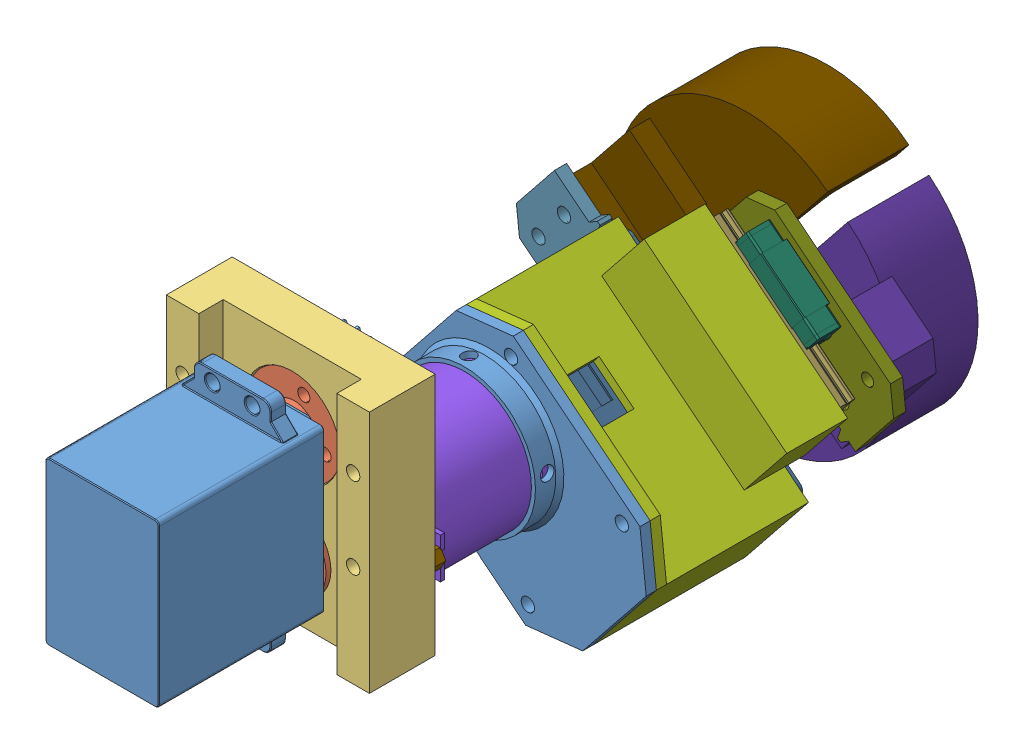
SolidWorks assembly Turntable assembly, configuration close. Lengths in mm.
Overall size (99.15 95.23 181.35).
25 component instances, 20 part files, 72 mates.
Components (placement in the parent):
- SM29BL-1: SM29BL [預設] at (0 0 1.5) size (28 54 48.8)
- SMS Servo Disc-1: SMS Servo Disc [預設] at (0 10 -8) x (-0.299611 -0.954061 0) z (0 0 1) size (23 23 6)
- Gear mount-1: Gear mount [預設] at (0 28.5 1.45) x (-1 0 0) z (0 -1 0) size (50 16.2 60)
- Gear spacer-1: Gear spacer [預設] at (0 10 -16) x (-0.299611 -0.954061 0) z (0 0 1) size (23 23 8)
- 1M 26T 4mm SMS hub-1: 1M 26T 4mm SMS hub [預設] at (0 10 -20) x (-0.299611 -0.954061 0) z (0 0 1) size (28 27.86 4)
- 1M 26T 4mm SMS hub-2: 1M 26T 4mm SMS hub [預設] at (0 -16 -19.95) x (-0.223358 0.974736 0) z (0 0 1) size (28 27.86 4)
- Washer_8x15x1.6mm-1: Washer_8x15x1.6mm [預設] at (0 -16 -21.55) size (15.32 15.32 1.62)
- Turntable Servo Mount-1: Turntable Servo Mount [預設] at (7.5485 -22.052 -92.95) x (0.625526 0.780203 0) z (0 0 1) size (58.5 60 42.5)
- Slip Ring-1: Slip Ring [預設] at (0 -16 -46.95) size (41 33 32.4)
- M3x6+5-1: M3x6+5 [預設] at (19 -16 -20.75) size (5.26 4.56 11)
- M3x6+5-2: M3x6+5 [預設] at (-19 -16 -20.75) size (5.26 4.56 11)
- UART Servo-1: UART Servo [預設] at (7.5485 -22.052 -86.25) x (0.780203 -0.625526 0) z (0 0 -1) size (56 22.53 44.45)
- Servo disc-1: Servo disc [Default] at (0 -16 -107.1) x (-0.33197 -0.94329 0) z (-0.94329 0.33197 0) size (20 4.5 20)
- MGN7 rail-1: MGN7 rail [70 mm] at (7.9835 -53.4824 -100.35) x (0.625526 0.780203 0) z (-0.780203 0.625526 0) size (7 4.8 40)
- MGN7 rail-2: MGN7 rail [70 mm] at (38.3215 -15.6426 -100.35) x (0.625526 0.780203 0) z (-0.780203 0.625526 0) size (7 4.8 40)
- 1M 26T 4mm SCS hub-1: 1M 26T 4mm SCS hub [預設] at (0 -16 -111.1) x (0.901745 0.432268 0) z (0 0 1) size (28 27.86 4)
- Turntable rack left-1: Turntable rack left [預設] at (-19.1907 -31.6956 -106.05) x (-0.780203 0.625526 0) z (0 0 -1) size (61.5 22.25 3)
- MGN7C-1: MGN7C [MGN7C] at (20.439 -1.3053 -102.8) x (0.625526 0.780203 0) z (-0.780203 0.625526 0) size (17 6.5 23.31)
- MGN7C-2: MGN7C [MGN7C] at (-5.3421 -42.7987 -102.8) x (0.625526 0.780203 0) z (-0.780203 0.625526 0) size (17 6.5 23.31)
- Turntable rack right-1: Turntable rack right [預設] at (25.3153 -5.2148 -106.05) x (0.780203 -0.625526 0) z (0 0 -1) size (46.5 22.25 3)
- Turntable Gripper Right-1: Turntable Gripper Right [預設] at (51.253 43.5228 -139.05) x (-0.780203 0.625526 0) z (0 0 1) size (35.43 66.5 30)
- Turntable Gripper left-1: Turntable Gripper left [預設] at (-2.8123 -13.7452 -139.05) x (-0.780203 0.625526 0) z (0 0 1) size (35.43 66.5 30)
- Turntable axle-1: Turntable axle [預設] at (7.5485 -22.052 -92.95) x (0.625526 0.780203 0) z (0 0 1) size (45 60 51.6)
- F697ZZ_7x17x5mm-1: F697ZZ_7x17x5mm [預設] at (0 -16 -9.75) x (-0.997972 -0.063648 0) z (0 0 -1) size (19 19 6.2)
- F697ZZ_7x17x5mm-2: F697ZZ_7x17x5mm [預設] at (0 -16 -9.55) x (-0.081847 0.996645 0) z (0 0 1) size (19 19 6.2)
Mates (geometry in assembly coordinates):
- 同軸心1: concentric anti-aligned: cylinder of SM29BL-1 through (0 10 -1.5) axis (0 0 -1) radius 1.1; cylinder of SMS Servo Disc-1 through (0 10 -8.001) axis (0 0 1) radius 1.65
- 重合/共線/共點1: coincident anti-aligned: plane of SM29BL-1 through (0 0 -6.5) normal (0 0 -1); plane of SMS Servo Disc-1 through (0 10 -6.5) normal (0 0 1)
- 重合/共線/共點2: coincident anti-aligned: plane of SM29BL-1 through (0 0 0) normal (0 0 -1)
- 同軸心2: concentric aligned: cylinder of SMS Servo Disc-1 through (0 10 -5) axis (0 0 -1) radius 11.5; cylinder of Gear mount-1 through (0 10 25.25) axis (0 0 -1) radius 11.75
- 平行1: parallel aligned: plane of SM29BL-1 through (14 20 42.3) normal (1 0 0); plane of Gear mount-1 through (25 -31.5 -14.75) normal (1 0 0)
- 同軸心3: concentric aligned: cylinder of Gear mount-1 through (0 -16 25.25) axis (0 0 -1) radius 9.5; cylinder of F607ZZ_7x19x6mm-1 through (0 -16 -5.55) axis (0 0 -1) radius 9.5
- 重合/共線/共點3: coincident anti-aligned: plane of Gear mount-1 through (-25 -31.5 -14.75) normal (0 0 -1); plane of F607ZZ_7x19x6mm-1 through (0 -16 -11.55) normal (0 0 1)
- 同軸心4: concentric aligned: cylinder of SMS Servo Disc-1 through (7.6325 7.6031 -5) axis (0 0 -1) radius 1.5; cylinder of Gear spacer-1 through (7.6325 7.6031 -8) axis (0 0 -1) radius 1.65
- 同軸心5: concentric anti-aligned: cylinder of SMS Servo Disc-1 through (0 10 -8.001) axis (0 0 1) radius 1.65; cylinder of Gear spacer-1 through (0 10 -8) axis (0 0 -1) radius 2.1
- 同軸心6: concentric anti-aligned: cylinder of Gear spacer-1 through (-2.3969 2.3675 -8) axis (0 0 -1) radius 1.65; cylinder of 1M 26T 4mm SMS hub-1 through (-2.3969 2.3675 -20.001) axis (0 0 1) radius 1.65
- 同軸心8: concentric anti-aligned: cylinder of Gear spacer-1 through (0 10 -8) axis (0 0 -1) radius 2.1; cylinder of 1M 26T 4mm SMS hub-1 through (0 10 -20.001) axis (0 0 1) radius 3.6
- 同軸心9: concentric anti-aligned: cylinder of F607ZZ_7x19x6mm-1 through (0 -16 -5.55) axis (0 0 -1) radius 3.5; cylinder of 1M 26T 4mm SMS hub-2 through (0 -16 -19.951) axis (0 0 1) radius 3.6
- 齒輪結合1: gear = 26 : 26 mm: circle of 1M 26T 4mm SMS hub-2; circle of 1M 26T 4mm SMS hub-1
- 相互對稱1: symmetric aligned: plane of SM29BL-1 through (-14 20 42.3) normal (0 1 0); plane of SM29BL-1 through (-14 -20 42.3) normal (0 -1 0)
- 相互對稱2: symmetric aligned: plane of SM29BL-1 through (14 20 42.3) normal (1 0 0); plane of SM29BL-1 through (-14 20 42.3) normal (-1 0 0)
- 重合/共線/共點7: coincident anti-aligned: plane of SMS Servo Disc-1 through (0 10 -8) normal (0 0 -1); plane of Gear spacer-1 through (0 10 -8) normal (0 0 1)
- 重合/共線/共點8: coincident anti-aligned: plane of Gear spacer-1 through (0 10 -16) normal (0 0 -1); plane of 1M 26T 4mm SMS hub-1 through (0 10 -16) normal (0 0 1)
- 重合/共線/共點9: coincident anti-aligned: plane of 1M 26T 4mm SMS hub-2 through (0 -16 -19.95) normal (0 0 -1); plane of Washer_8x15x1.6mm-1 through (0 -16 -19.95) normal (0 0 1)
- 同軸心10: concentric anti-aligned: cylinder of 1M 26T 4mm SMS hub-2 through (0 -16 -19.951) axis (0 0 1) radius 3.6; cylinder of Washer_8x15x1.6mm-1 through (0 -16 -19.95) axis (0 0 -1) radius 4
- 重合/共線/共點10: coincident anti-aligned: plane of Washer_8x15x1.6mm-1 through (0 -16 -21.55) normal (0 0 -1); plane of Slip Ring-1 through (8.5 -21 -21.55) normal (0 0 1)
- 同軸心11: concentric anti-aligned: cylinder of Washer_8x15x1.6mm-1 through (0 -16 -19.95) axis (0 0 -1) radius 4; cylinder of Slip Ring-1 through (0 -16 -46.951) axis (0 0 1) radius 3.5
- 平行2: parallel aligned: plane of Gear mount-1 through (25 -31.5 -14.75) normal (1 0 0); plane of Slip Ring-1 through (20.5 -21 -20.55) normal (1 0 0)
- 同軸心14: concentric anti-aligned: cylinder of Gear mount-1 through (-19 -16 -14.75) axis (0 0 -1) radius 1.25; cylinder of Slip Ring-1 through (-19 -16 -21.55) axis (0 0 1) radius 1.5
- 同軸心15: concentric aligned: cylinder of Gear mount-1 through (19 -16 -14.75) axis (0 0 -1) radius 1.25; cylinder of M3x6+5-1 through (19 -16 -9.75) axis (0 0 -1) radius 1.5
- 重合/共線/共點12: coincident anti-aligned: plane of Gear mount-1 through (-25 -31.5 -14.75) normal (0 0 -1); plane of M3x6+5-1 through (19 -16 -14.75) normal (0 0 1)
- 同軸心16: concentric aligned: cylinder of Gear mount-1 through (-19 -16 -14.75) axis (0 0 -1) radius 1.25; cylinder of M3x6+5-2 through (-19 -16 -9.75) axis (0 0 -1) radius 1.5
- 重合/共線/共點13: coincident anti-aligned: plane of Gear mount-1 through (-25 -31.5 -14.75) normal (0 0 -1); plane of M3x6+5-2 through (-19 -16 -14.75) normal (0 0 1)
- 同軸心17: concentric aligned: cylinder of Turntable Servo Mount-1 through (-14.8892 -10.4712 -86.95) axis (0 0 -1) radius 1.65; cylinder of UART Servo-1 through (-14.8892 -10.4712 -95.45) axis (0 0 -1) radius 2.15
- 同軸心18: concentric aligned: cylinder of Turntable Servo Mount-1 through (-8.6339 -2.6692 -86.95) axis (0 0 -1) radius 1.65; cylinder of UART Servo-1 through (-8.6339 -2.6692 -95.45) axis (0 0 -1) radius 2.15
- 重合/共線/共點15: coincident anti-aligned: plane of Turntable Servo Mount-1 through (7.5485 -22.052 -92.95) normal (0 0 -1); plane of UART Servo-1 through (-14.3109 -17.3435 -92.95) normal (0 0 1)
- 同軸心19: concentric anti-aligned: cylinder of UART Servo-1; cylinder of Servo disc-1 through (0 -16 -106.2) axis (0 0 1) radius 2.25
- 重合/共線/共點16: coincident anti-aligned: plane of UART Servo-1 through (0 -16 -106.2) normal (0 0 -1); plane of Servo disc-1 through (0 -16 -106.2) normal (0 0 1)
- 同軸心20: concentric anti-aligned: cylinder of Turntable Servo Mount-1 through (4.0825 -50.3548 -100.95) axis (0 0 1) radius 0.8; cylinder of MGN7 rail-1 through (4.0825 -50.3548 -100.45) axis (0 0 -1) radius 2.1
- 同軸心21: concentric anti-aligned: cylinder of Turntable Servo Mount-1 through (-7.6206 -40.9719 -100.95) axis (0 0 1) radius 0.8; cylinder of MGN7 rail-1 through (-7.6206 -40.9719 -100.45) axis (0 0 -1) radius 2.1
- 重合/共線/共點17: coincident anti-aligned: plane of Turntable Servo Mount-1 through (6.8064 -58.9473 -97.95) normal (0 0 -1); plane of MGN7 rail-1 through (-25.2888 -31.036 -97.95) normal (0 0 1)
- 同軸心22: concentric anti-aligned: cylinder of Turntable Servo Mount-1 through (34.4205 -12.5149 -100.95) axis (0 0 1) radius 0.8; cylinder of MGN7 rail-2 through (34.4205 -12.5149 -100.45) axis (0 0 -1) radius 2.1
- 同軸心23: concentric anti-aligned: cylinder of Turntable Servo Mount-1 through (22.7175 -3.132 -100.95) axis (0 0 1) radius 0.8; cylinder of MGN7 rail-2 through (22.7175 -3.132 -97.949) axis (0 0 -1) radius 1.2
- 重合/共線/共點18: coincident anti-aligned: plane of Turntable Servo Mount-1 through (43.3997 -13.3054 -97.95) normal (0 0 -1); plane of MGN7 rail-2 through (5.0492 6.8038 -97.95) normal (0 0 1)
- 同軸心24: concentric aligned: cylinder of Servo disc-1; cylinder of 1M 26T 4mm SCS hub-1 through (0 -16 -111.101) axis (0 0 1) radius 3
- 重合/共線/共點19: coincident anti-aligned: plane of Servo disc-1 through (0 -16 -107.1) normal (0 0 -1); plane of 1M 26T 4mm SCS hub-1 through (0 -16 -107.1) normal (0 0 1)
- 同軸心25: concentric anti-aligned: cylinder of Servo disc-1 through (6.3122 -12.9741 -105.1) axis (0 0 -1) radius 1.25; cylinder of 1M 26T 4mm SCS hub-1 through (6.3122 -12.9741 -111.101) axis (0 0 1) radius 1.6
- 重合/共線/共點20: coincident anti-aligned: plane of MGN7 rail-2 through (5.0492 6.8038 -102.75) normal (0 0 -1); plane of MGN7C-1 through (15.1726 2.917 -102.75) normal (0 0 1)
- 同軸心26: concentric anti-aligned: cylinder of MGN7 rail-2; cylinder of MGN7C-1 through (31.4682 -5.5337 -101.25) axis (-0.780203 0.625526 0) radius 0.8
- 限制距離2: limit distance = 5.8296 mm aligned: plane of MGN7C-1 through (11.6617 5.7319 -102.8) normal (-0.780203 0.625526 0); plane of MGN7 rail-2 through (4.8615 6.5698 -101.25) normal (-0.780203 0.625526 0)
- 同軸心27: concentric anti-aligned: cylinder of MGN7 rail-1; cylinder of MGN7C-2 through (5.6871 -47.0271 -101.25) axis (-0.780203 0.625526 0) radius 0.8
- 同軸心28: concentric anti-aligned: cylinder of MGN7 rail-1 through (-25.4765 -31.2701 -101.25) axis (0.780203 -0.625526 0) radius 0.8; circle of MGN7C-2
- 限制距離4: limit distance = 5.8296 mm aligned: plane of MGN7C-2 through (3.4352 -49.8358 -102.8) normal (0.780203 -0.625526 0); plane of MGN7 rail-1 through (5.7316 -56.2911 -101.25) normal (0.780203 -0.625526 0)
- 同軸心29: concentric aligned: cylinder of MGN7C-1 through (13.565 -3.4844 -103.55) axis (0 0 -1) radius 1; cylinder of Turntable rack right-1 through (13.565 -3.4844 -106.05) axis (0 0 -1) radius 1.65
- 同軸心30: concentric aligned: cylinder of MGN7C-1 through (19.8066 -8.4886 -103.55) axis (0 0 -1) radius 1; cylinder of Turntable rack right-1 through (19.8066 -8.4886 -106.05) axis (0 0 -1) radius 1.65
- 重合/共線/共點21: coincident anti-aligned: plane of MGN7C-1 through (15.1726 2.917 -106.05) normal (0 0 -1); plane of Turntable rack right-1 through (25.3153 -5.2148 -106.05) normal (0 0 1)
- 同軸心32: concentric anti-aligned: cylinder of Turntable rack right-1 through (40.1849 -10.728 -99.05) axis (0 0 -1) radius 1.5; cylinder of Turntable Gripper Right-1 through (40.1849 -10.728 -115.05) axis (0 0 1) radius 1.25
- 同軸心33: concentric anti-aligned: cylinder of Turntable rack right-1 through (33.9297 -18.53 -99.05) axis (0 0 -1) radius 1.65; cylinder of Turntable Gripper Right-1 through (33.9297 -18.53 -115.05) axis (0 0 1) radius 1.25
- 重合/共線/共點22: coincident anti-aligned: plane of Turntable rack right-1 through (25.3153 -5.2148 -109.05) normal (0 0 -1); plane of Turntable Gripper Right-1 through (2.1492 -17.7231 -109.05) normal (0 0 1)
- 同軸心34: concentric aligned: cylinder of Turntable rack left-1 through (-12.216 -44.9778 -106.049) axis (0 0 -1) radius 1.65; cylinder of MGN7C-2 through (-12.216 -44.9778 -103.55) axis (0 0 -1) radius 1
- 重合/共線/共點23: coincident anti-aligned: plane of Turntable rack left-1 through (-19.1907 -31.6956 -106.05) normal (0 0 1); plane of MGN7C-2 through (-10.6084 -38.5764 -106.05) normal (0 0 -1)
- 同軸心35: concentric aligned: cylinder of Turntable rack left-1 through (-5.9744 -49.982 -106.049) axis (0 0 -1) radius 1.65; cylinder of MGN7C-2 through (-5.9744 -49.982 -103.55) axis (0 0 -1) radius 1
- RackPinionMate1: rack pinion = 26 mm: line of Turntable rack left-1 through (10.7026 -41.2431 -109.05) axis (-0.780203 0.625526 0); circle of 1M 26T 4mm SCS hub-1
- RackPinionMate2: rack pinion = 26 mm: line of Turntable rack right-1 through (1.2735 -0.3587 -109.05) axis (0.780203 -0.625526 0); circle of 1M 26T 4mm SCS hub-1
- 重合/共線/共點24: coincident anti-aligned: plane of Turntable rack left-1 through (-19.1907 -31.6956 -109.05) normal (0 0 -1); plane of Turntable Gripper left-1 through (-2.8123 -13.7452 -109.05) normal (0 0 1)
- 同軸心36: concentric anti-aligned: cylinder of Turntable rack left-1 through (-40.8481 -20.7403 -106.049) axis (0 0 -1) radius 1.65; cylinder of Turntable Gripper left-1 through (-40.8481 -20.7403 -115.05) axis (0 0 1) radius 1.25
- 同軸心37: concentric anti-aligned: cylinder of Turntable rack left-1 through (-34.5928 -12.9383 -106.049) axis (0 0 -1) radius 1.65; cylinder of Turntable Gripper left-1 through (-34.5928 -12.9383 -115.05) axis (0 0 1) radius 1.25
- 重合/共線/共點25: coincident anti-aligned: plane of Turntable Servo Mount-1 through (7.5485 -22.052 -55.45) normal (0 0 1); plane of Turntable axle-1 through (7.5485 -22.052 -55.45) normal (0 0 -1)
- 同軸心38: concentric aligned: cylinder of Turntable Servo Mount-1 through (9.6298 -47.4324 -52.949) axis (0 0 -1) radius 1.65; cylinder of Turntable axle-1 through (9.6298 -47.4324 -52.949) axis (0 0 -1) radius 1.65
- 同軸心39: concentric aligned: cylinder of Turntable Servo Mount-1 through (-17.6773 -25.539 -52.949) axis (0 0 -1) radius 1.65; cylinder of Turntable axle-1 through (-17.6773 -25.539 -52.949) axis (0 0 -1) radius 1.65
- 同軸心40: concentric aligned: cylinder of Slip Ring-1; cylinder of Turntable axle-1 through (0 -16 -3.85) axis (0 0 -1) radius 3.25
- 重合/共線/共點26: coincident anti-aligned: plane of Slip Ring-1; plane of Turntable axle-1 through (7.5485 -22.052 -52.95) normal (0 0 1)
- 同軸心41: concentric anti-aligned: cylinder of Gear mount-1 through (0 -16 25.25) axis (0 0 -1) radius 9.5; cylinder of F697ZZ_7x17x5mm-1 through (0 -16 -14.75) axis (0 0 1) radius 8.5
- 重合/共線/共點27: coincident anti-aligned: plane of Gear mount-1 through (-25 -31.5 -14.75) normal (0 0 -1); plane of F697ZZ_7x17x5mm-1 through (0 -16 -14.75) normal (0 0 1)
- 同軸心43: concentric aligned: cylinder of Gear mount-1 through (0 -16 25.25) axis (0 0 -1) radius 9.5; cylinder of F697ZZ_7x17x5mm-2 through (0 -16 -4.55) axis (0 0 -1) radius 8.5
- 重合/共線/共點28: coincident anti-aligned: plane of Gear mount-1 through (17 -31.5 -4.55) normal (0 0 1); plane of F697ZZ_7x17x5mm-2 through (0 -16 -4.55) normal (0 0 -1)
- 平行相距1: distance = 5 mm anti-aligned: plane of SM29BL-1 through (0 0 6.45) normal (0 0 -1); plane of Gear mount-1 through (25 -31.5 1.45) normal (0 0 1)
- 重合/共線/共點29: coincident anti-aligned: plane of 1M 26T 4mm SMS hub-2 through (0 -16 -15.95) normal (0 0 1); plane of F697ZZ_7x17x5mm-1 through (0 -16 -15.95) normal (0 0 -1)
